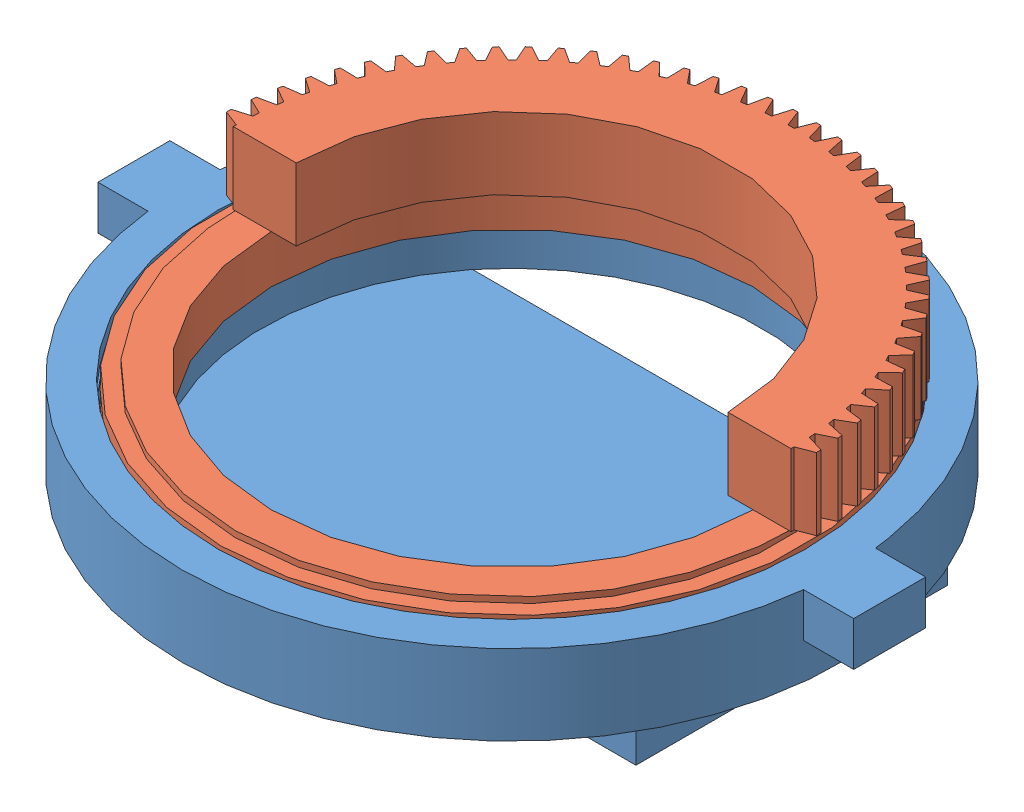
SolidWorks assembly MainTurretAsm, configuration Default. Lengths in mm.
Overall size (266.7 68.5 232.69).
2 component instances, 2 part files, 3 mates.
Components (placement in the parent):
- MainTurretBase-1: MainTurretBase [Default] at (174.5004 204.266 347.3401) size (266.7 40.96 232.69)
- MainTurretGear-1: MainTurretGear [Inch - Spur gear 10DP 80T 20PA 1FW ---S80N3.0H2.0L0.03125N] at (173.985 195.7385 346.695) x (0 1 0) z (0 0 1) size (42.27 208.18 206.91)
Mates (geometry in assembly coordinates):
- Parallel2: parallel anti-aligned: plane of MainTurretBase-1 through (278.1451 178.0405 347.3401) normal (0 1 0); plane of MainTurretGear-1 through (173.985 178.866 243.876) normal (0 -1 0)
- Tangent2: tangent: circle of MainTurretBase-1; circle of MainTurretGear-1
- Perpendicular3: perpendicular: plane of MainTurretGear-1 through (296.347 195.7375 346.695) normal (0 0 1)
